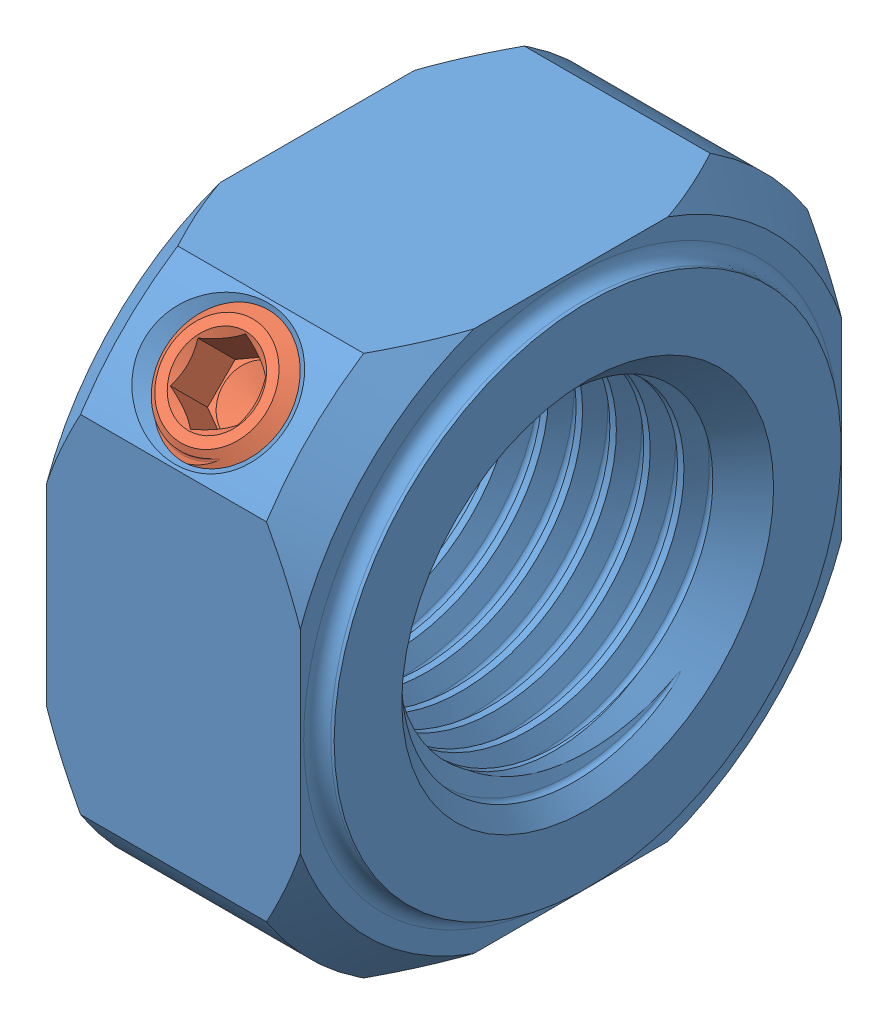
SolidWorks assembly Гайка М10х1, configuration По умолчанию. Lengths in mm.
Overall size (8 16.18 16.18).
2 component instances, 2 part files, 2 mates.
Components (placement in the parent):
- Гайка-1: Гайка [По умолчанию] at origin size (8 16.09 16.09)
- Винт М4х4-1: Винт М4х4 [По умолчанию] at (3.75 6.7175 6.7175) x (0 -0.707107 -0.707107) z (0 -0.707107 0.707107) size (4.07 4.62 4)
Mates (geometry in assembly coordinates):
- Концентричный2: concentric: cylinder of Гайка-1 through (3.75 6.7175 6.7175) axis (0 0.707107 0.707107) radius 1.65; cylinder of Винт М4х4-1 through (3.75 5.3033 5.3033) axis (0 0.707107 0.707107) radius 2
- Касательность1: tangent aligned: cylinder of Гайка-1 through (0 0 0) axis (-1 0 0) radius 9.5; plane of Винт М4х4-1 through (5.25 6.7175 6.7175) normal (0 0.707107 0.707107)
